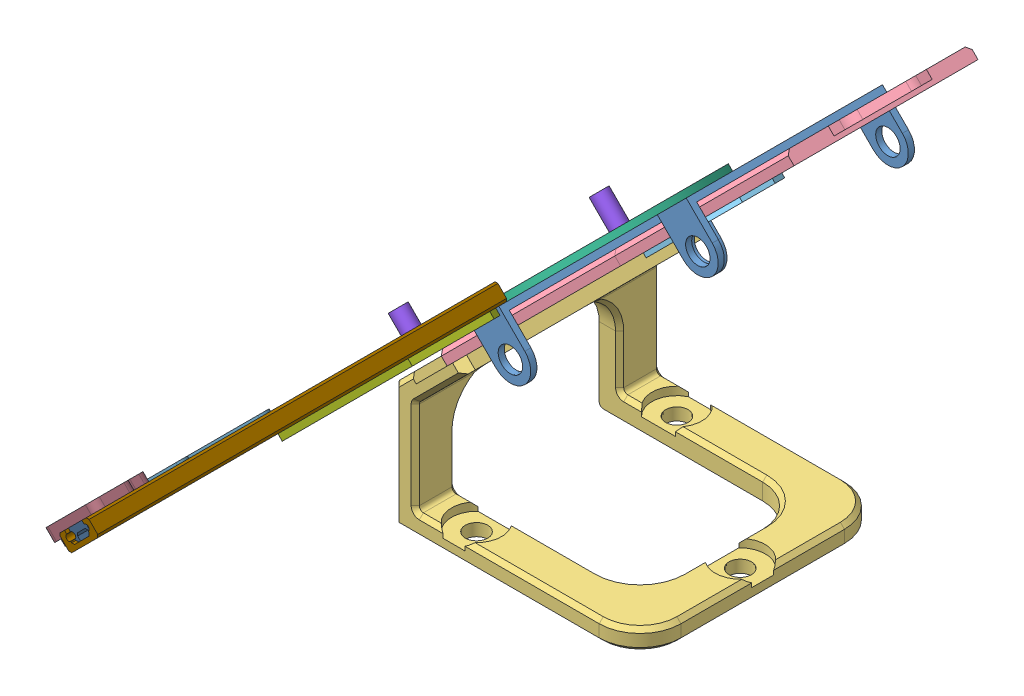
SolidWorks assembly RivetingStation, configuration Default. Lengths in mm.
Overall size (96.52 119.45 167).
19 component instances, 14 part files, 52 mates.
Components (placement in the parent):
- Bearing Housing^Base Model-1: Bearing Housing^Base Model [Default] at (-42.6759 40.9602 30) x (0 0 1) z (0.707107 0.707107 0) size (48 14 10)
- M4StandardWasher-1: M4StandardWasher [Default] at (-45.1508 50.5061 102.1128) x (0.707107 0.707107 0) z (0 0 1) size (9 0.8 9)
- Base-1: Base [Default] at origin size (60 42.73 60)
- BridgePlate^RivetingStation-1: BridgePlate^RivetingStation [Default] at (-33.4835 53.6881 30) x (0.707107 0.707107 0) z (-0.707107 0.707107 0) size (60 45 3) (virtual)
- Bearing Housing^Base Model-2: Bearing Housing^Base Model [Default] at (3.1702 86.8063 30) x (0 0 1) z (0.707107 0.707107 0) size (48 14 10)
- BridgePlate^RivetingStation-2: BridgePlate^RivetingStation [Default] at (8.9429 96.1145 30) x (0.707107 0.707107 0) z (-0.707107 0.707107 0) size (60 45 3) (virtual)
- Part3^RivetingStation-1: Part3^RivetingStation [Default] at (-12.2703 74.9013 30) x (-0.707107 -0.707107 0) z (0.707107 -0.707107 0) size (30 24 1) (virtual)
- Plate-TriStar-1: Plate-TriStar [Default] at (-45.1508 50.5061 30) x (0 0 1) z (0.707107 -0.707107 0) size (60 60 1.5)
- Part4^RivetingStation-1: Part4^RivetingStation [Default] at (-43.0294 48.3848 30) x (0.707107 0.707107 0) z (-0.707107 0.707107 0) size (50 95 1.5) (virtual)
- PlateMount^RivetingStation-1: PlateMount^RivetingStation [Default] at (-57.5251 33.8891 5.4287) x (0.707107 0.707107 0) z (-0.707107 0.707107 0) size (4 4 10) (virtual)
- PlateMount^RivetingStation-2: PlateMount^RivetingStation [Default] at (-57.5251 33.8891 54.5713) x (0.707107 0.707107 0) z (-0.707107 0.707107 0) size (4 4 10) (virtual)
- Rail^RivetingStation-1: Rail^RivetingStation [Default] at (-35.2513 61.1127 62) x (0.707107 0.707107 0) z (0 0 1) size (10 4 100) (virtual)
- Part5^RivetingStation-1: Part5^RivetingStation [Default] at (-35.6048 61.4663 161.0477) x (-0.707107 -0.707107 0) z (0 0 -1) size (6 3 15) (virtual)
- WasherClampUpper^RivetingStation-1: WasherClampUpper^RivetingStation [Default] at (-41.9688 53.6881 55.7977) x (0.707107 0.707107 0) z (-0.707107 0.707107 0) size (8 90 1.5) (virtual)
- M4StandardWasher-2: M4StandardWasher [Default] at (-45.1508 50.5061 72.1128) x (0.707107 0.707107 0) z (0 0 1) size (9 0.8 9)
- WasherClampLower^RivetingStation-1: WasherClampLower^RivetingStation [Default] at (-45.1508 50.5061 57.1128) x (0.707107 0.707107 0) z (-0.707107 0.707107 0) size (8 80 1.5) (virtual)
- ClampRailConnector^RivetingStation-1: ClampRailConnector^RivetingStation [Default] at (-36.6655 62.5269 153.2977) x (0.707107 0.707107 0) z (-0.707107 0.707107 0) size (17 20 3) (virtual)
- ClampLink^RivetingStation-1: ClampLink^RivetingStation [Default] at (-42.3223 55.4558 109.7977) x (0.51349 0.51349 0.6875) z (-0.707107 0.707107 0) size (4 20 1.5) (virtual)
- ClampLink^RivetingStation-2: ClampLink^RivetingStation [Default] at (-42.3223 55.4558 129.7977) x (0.51349 0.51349 0.6875) z (-0.707107 0.707107 0) size (4 20 1.5) (virtual)
Mates (geometry in assembly coordinates):
- Coincident1: coordinate: point of Base-1; point of assembly
- Parallel1: parallel: line of Bearing Housing^Base Model-1 through (-47.6256 45.9099 6) axis (0 0 1); line of Base-1 through (-59.7071 30.2929 1) axis (0 0 1)
- Coincident2: coincident: plane of Bearing Housing^Base Model-1 through (-39.4939 51.9203 7.5) normal (0.707107 -0.707107 0); plane of BridgePlate^RivetingStation-1 through (-35.6048 55.8094 30) normal (-0.707107 0.707107 0)
- Coincident3: coincident: plane of Base-1 through (-43.5858 43.5858 0) normal (-0.707107 0.707107 0); plane of BridgePlate^RivetingStation-1 through (-33.4835 53.6881 30) normal (0.707107 -0.707107 0)
- Concentric2: concentric: cylinder of Base-1 through (-44.4437 28.5858 36) axis (-0.707107 0.707107 0) radius 2; cylinder of BridgePlate^RivetingStation-1 through (-55.0503 39.1924 36) axis (0.707107 -0.707107 0) radius 2
- Concentric3: concentric: cylinder of Base-1 through (-40.201 32.8284 18) axis (-0.707107 0.707107 0) radius 2; cylinder of BridgePlate^RivetingStation-1 through (-50.8076 43.435 18) axis (0.707107 -0.707107 0) radius 2
- Coincident5: coincident: plane of Bearing Housing^Base Model-1 through (-39.4939 51.9203 52.5) normal (0 0 -1); plane of BridgePlate^RivetingStation-1 through (-56.818 34.5962 52.5) normal (0 0 1)
- Coincident6: coincident: plane of BridgePlate^RivetingStation-1 through (-35.6048 55.8094 30) normal (-0.707107 0.707107 0); plane of Bearing Housing^Base Model-2 through (6.3522 97.7664 7.5) normal (0.707107 -0.707107 0)
- Coincident7: coincident: plane of BridgePlate^RivetingStation-1 through (-56.818 34.5962 52.5) normal (0 0 1); plane of Bearing Housing^Base Model-2 through (6.3522 97.7664 52.5) normal (0 0 -1)
- Coincident9: coincident: plane of Bearing Housing^Base Model-1 through (-42.6759 40.9602 30) normal (-0.707107 -0.707107 0); plane of Base-1 through (-42.3223 40.6066 60) normal (0.707107 0.707107 0)
- Coincident10: coincident: plane of BridgePlate^RivetingStation-1 through (-14.3916 77.0226 7.5) normal (0.707107 0.707107 0); plane of BridgePlate^RivetingStation-2 through (-14.3916 77.0226 7.5) normal (-0.707107 -0.707107 0)
- Coincident11: coincident: plane of BridgePlate^RivetingStation-1 through (-35.6048 55.8094 30) normal (-0.707107 0.707107 0); plane of BridgePlate^RivetingStation-2 through (6.8216 98.2358 30) normal (-0.707107 0.707107 0)
- Coincident12: coincident: plane of BridgePlate^RivetingStation-1 through (-56.818 34.5962 52.5) normal (0 0 1); plane of BridgePlate^RivetingStation-2 through (-14.3916 77.0226 52.5) normal (0 0 1)
- Coincident13: coincident: plane of BridgePlate^RivetingStation-2 through (8.9429 96.1145 30) normal (0.707107 -0.707107 0); plane of Part3^RivetingStation-1 through (-12.2703 74.9013 30) normal (-0.707107 0.707107 0)
- Concentric4: concentric: cylinder of BridgePlate^RivetingStation-1 through (-18.9878 75.2548 24) axis (0.707107 -0.707107 0) radius 2; cylinder of Part3^RivetingStation-1 through (-13.331 69.598 24) axis (-0.707107 0.707107 0) radius 2
- Concentric5: concentric: cylinder of BridgePlate^RivetingStation-1 through (-18.9878 75.2548 36) axis (0.707107 -0.707107 0) radius 2; cylinder of Part3^RivetingStation-1 through (-13.331 69.598 36) axis (-0.707107 0.707107 0) radius 2
- Coincident14: coincident: plane of Bearing Housing^Base Model-1 through (-40.5546 52.981 6) normal (-0.707107 0.707107 0); plane of Plate-TriStar-1 through (-44.0901 49.4454 30) normal (0.707107 -0.707107 0)
- Concentric7: concentric: cylinder of Bearing Housing^Base Model-1 through (-50.1005 55.4558 15) axis (0.707107 -0.707107 0) radius 2; cylinder of Plate-TriStar-1 through (-44.0901 49.4454 15) axis (-0.707107 0.707107 0) radius 2
- Concentric8: concentric: cylinder of Bearing Housing^Base Model-1 through (-50.1005 55.4558 45) axis (0.707107 -0.707107 0) radius 2; cylinder of Plate-TriStar-1 through (-44.0901 49.4454 45) axis (-0.707107 0.707107 0) radius 2
- Coincident18: coincident: plane of BridgePlate^RivetingStation-1 through (-35.6048 55.8094 30) normal (-0.707107 0.707107 0); plane of Part4^RivetingStation-1 through (-43.0294 48.3848 30) normal (0.707107 -0.707107 0)
- Concentric9: concentric: cylinder of BridgePlate^RivetingStation-1 through (-50.8076 43.435 18) axis (0.707107 -0.707107 0) radius 2; cylinder of Part4^RivetingStation-1 through (-50.4541 43.0815 18) axis (0.707107 -0.707107 0) radius 2
- Concentric10: concentric: cylinder of BridgePlate^RivetingStation-1 through (-50.8076 43.435 42) axis (0.707107 -0.707107 0) radius 2; cylinder of Part4^RivetingStation-1 through (-50.4541 43.0815 42) axis (0.707107 -0.707107 0) radius 2
- Coincident19: coincident: plane of M4StandardWasher-1 through (-45.1508 50.5061 102.1128) normal (0.707107 -0.707107 0); plane of Plate-TriStar-1 through (-45.1508 50.5061 30) normal (-0.707107 0.707107 0)
- Concentric12: concentric: cylinder of Part4^RivetingStation-1 through (-58.5858 34.9497 5.4287) axis (0.707107 -0.707107 0) radius 2; cylinder of PlateMount^RivetingStation-1 through (-64.5962 40.9602 5.4287) axis (0.707107 -0.707107 0) radius 2
- Coincident20: coincident: plane of Part4^RivetingStation-1 through (-43.0294 48.3848 30) normal (0.707107 -0.707107 0); plane of PlateMount^RivetingStation-1 through (-57.5251 33.8891 5.4287) normal (0.707107 -0.707107 0)
- Concentric13: concentric: cylinder of Part4^RivetingStation-1 through (-58.5858 34.9497 54.5713) axis (0.707107 -0.707107 0) radius 2; cylinder of PlateMount^RivetingStation-2 through (-64.5962 40.9602 54.5713) axis (0.707107 -0.707107 0) radius 2
- Coincident21: coincident: plane of Part4^RivetingStation-1 through (-43.0294 48.3848 30) normal (0.707107 -0.707107 0); plane of PlateMount^RivetingStation-2 through (-57.5251 33.8891 54.5713) normal (0.707107 -0.707107 0)
- Coincident22: coincident: plane of Part4^RivetingStation-1 through (-44.0901 49.4454 30) normal (-0.707107 0.707107 0); plane of Rail^RivetingStation-1 through (-33.837 59.6985 162) normal (0.707107 -0.707107 0)
- Concentric14: concentric: cylinder of Part4^RivetingStation-1 through (-26.766 52.6274 82) axis (-0.707107 0.707107 0) radius 2; cylinder of Rail^RivetingStation-1 through (106.8772 -81.0158 82) axis (-0.707107 0.707107 0) radius 2
- Concentric15: concentric: cylinder of Part4^RivetingStation-1 through (-26.766 52.6274 72) axis (-0.707107 0.707107 0) radius 2; cylinder of Rail^RivetingStation-1 through (106.8772 -81.0158 72) axis (-0.707107 0.707107 0) radius 2
- Coincident23: coincident: plane of Part4^RivetingStation-1 through (-44.0901 49.4454 30) normal (-0.707107 0.707107 0); plane of Rail^RivetingStation-1 through (-33.837 59.6985 162) normal (0.707107 -0.707107 0)
- Coincident24: coincident: plane of Rail^RivetingStation-1 through (-36.6655 62.5269 162) normal (-0.707107 0.707107 0); plane of Part5^RivetingStation-1 through (-34.5442 64.6482 146.0477) normal (-0.707107 0.707107 0)
- Coincident25: coincident: plane of Rail^RivetingStation-1 through (-33.1299 63.234 162) normal (-0.707107 -0.707107 0); plane of Part5^RivetingStation-1 through (-34.5442 64.6482 146.0477) normal (0.707107 0.707107 0)
- Coincident26: coincident: plane of Plate-TriStar-1 through (-45.1508 50.5061 30) normal (-0.707107 0.707107 0); plane of WasherClampUpper^RivetingStation-1 through (-41.9688 53.6881 55.7977) normal (0.707107 -0.707107 0)
- Tangent1: tangent: cylinder of M4StandardWasher-1 through (-45.7164 51.0718 102.1128) axis (0.707107 -0.707107 0) radius 4.5; plane of WasherClampUpper^RivetingStation-1 through (-43.0294 54.7487 55.7977) normal (-0.707107 -0.707107 0)
- Parallel3: parallel: plane of Rail^RivetingStation-1 through (-31.7157 64.6482 162) normal (0.707107 0.707107 0); plane of WasherClampUpper^RivetingStation-1 through (-40.201 57.5772 155.7977) normal (0.707107 0.707107 0)
- Coincident29: coincident: plane of Plate-TriStar-1 through (-45.1508 50.5061 30) normal (-0.707107 0.707107 0); plane of M4StandardWasher-2 through (-45.1508 50.5061 72.1128) normal (0.707107 -0.707107 0)
- Coincident30: coincident: plane of Plate-TriStar-1 through (-45.1508 50.5061 30) normal (-0.707107 0.707107 0); plane of WasherClampLower^RivetingStation-1 through (-45.1508 50.5061 57.1128) normal (0.707107 -0.707107 0)
- Coincident32: coincident: plane of Part5^RivetingStation-1 through (-34.5442 64.6482 146.0477) normal (-0.707107 0.707107 0); plane of ClampRailConnector^RivetingStation-1 through (-36.6655 62.5269 153.2977) normal (0.707107 -0.707107 0)
- Concentric20: concentric: cylinder of Part5^RivetingStation-1 through (-22.5233 48.3848 155.0477) axis (-0.707107 0.707107 0) radius 1; cylinder of ClampRailConnector^RivetingStation-1 through (-38.0797 63.9411 155.0477) axis (0.707107 -0.707107 0) radius 1
- Concentric21: concentric: cylinder of Part5^RivetingStation-1 through (-22.5233 48.3848 151.5477) axis (-0.707107 0.707107 0) radius 1; cylinder of ClampRailConnector^RivetingStation-1 through (-38.0797 63.9411 151.5477) axis (0.707107 -0.707107 0) radius 1
- Concentric22: concentric: cylinder of WasherClampUpper^RivetingStation-1 through (-40.5546 50.1525 140.7977) axis (-0.707107 0.707107 0) radius 1; cylinder of ClampRailConnector^RivetingStation-1 through (-42.6759 52.2739 140.7977) axis (-0.707107 0.707107 0) radius 1
- Concentric23: concentric: cylinder of WasherClampUpper^RivetingStation-1 through (-38.7868 51.9203 109.7977) axis (-0.707107 0.707107 0) radius 1; cylinder of ClampLink^RivetingStation-1 through (-43.383 56.5165 109.7977) axis (0.707107 -0.707107 0) radius 1
- Coincident33: coincident: plane of WasherClampUpper^RivetingStation-1 through (-43.0294 54.7487 55.7977) normal (-0.707107 0.707107 0); plane of ClampLink^RivetingStation-1 through (-42.3223 55.4558 109.7977) normal (0.707107 -0.707107 0)
- Concentric24: concentric: cylinder of WasherClampLower^RivetingStation-1 through (-46.565 44.1421 121.4166) axis (-0.707107 0.707107 0) radius 1; cylinder of ClampLink^RivetingStation-1 through (-51.1612 48.7383 121.4166) axis (0.707107 -0.707107 0) radius 1
- Coincident34: coincident: plane of WasherClampUpper^RivetingStation-1 through (-43.0294 54.7487 55.7977) normal (-0.707107 0.707107 0); plane of ClampLink^RivetingStation-2 through (-42.3223 55.4558 129.7977) normal (0.707107 -0.707107 0)
- Concentric25: concentric: cylinder of WasherClampUpper^RivetingStation-1 through (-38.7868 51.9203 129.7977) axis (-0.707107 0.707107 0) radius 1; cylinder of ClampLink^RivetingStation-2 through (-43.383 56.5165 129.7977) axis (0.707107 -0.707107 0) radius 1
- Concentric26: concentric: cylinder of WasherClampLower^RivetingStation-1 through (-46.565 44.1421 141.4166) axis (-0.707107 0.707107 0) radius 1; cylinder of ClampLink^RivetingStation-2 through (-51.1612 48.7383 141.4166) axis (0.707107 -0.707107 0) radius 1
- Tangent5: tangent: cylinder of M4StandardWasher-1 through (-45.7164 51.0718 102.1128) axis (0.707107 -0.707107 0) radius 4.5; cylinder of WasherClampLower^RivetingStation-1 through (-48.3327 49.4454 107.3089) axis (0.707107 -0.707107 0) radius 1.5
- Tangent6: tangent: cylinder of M4StandardWasher-1 through (-45.7164 51.0718 102.1128) axis (0.707107 -0.707107 0) radius 4.5; cylinder of WasherClampLower^RivetingStation-1 through (-48.3327 49.4454 96.9166) axis (0.707107 -0.707107 0) radius 1.5
- Tangent7: tangent: cylinder of M4StandardWasher-2 through (-45.7164 51.0718 72.1128) axis (0.707107 -0.707107 0) radius 4.5; cylinder of WasherClampLower^RivetingStation-1 through (-48.3327 49.4454 77.3089) axis (0.707107 -0.707107 0) radius 1.5
- Tangent8: tangent: plane of WasherClampUpper^RivetingStation-1 through (-43.0294 54.7487 55.7977) normal (-0.707107 -0.707107 0); cylinder of M4StandardWasher-2 through (-45.7164 51.0718 72.1128) axis (0.707107 -0.707107 0) radius 4.5
